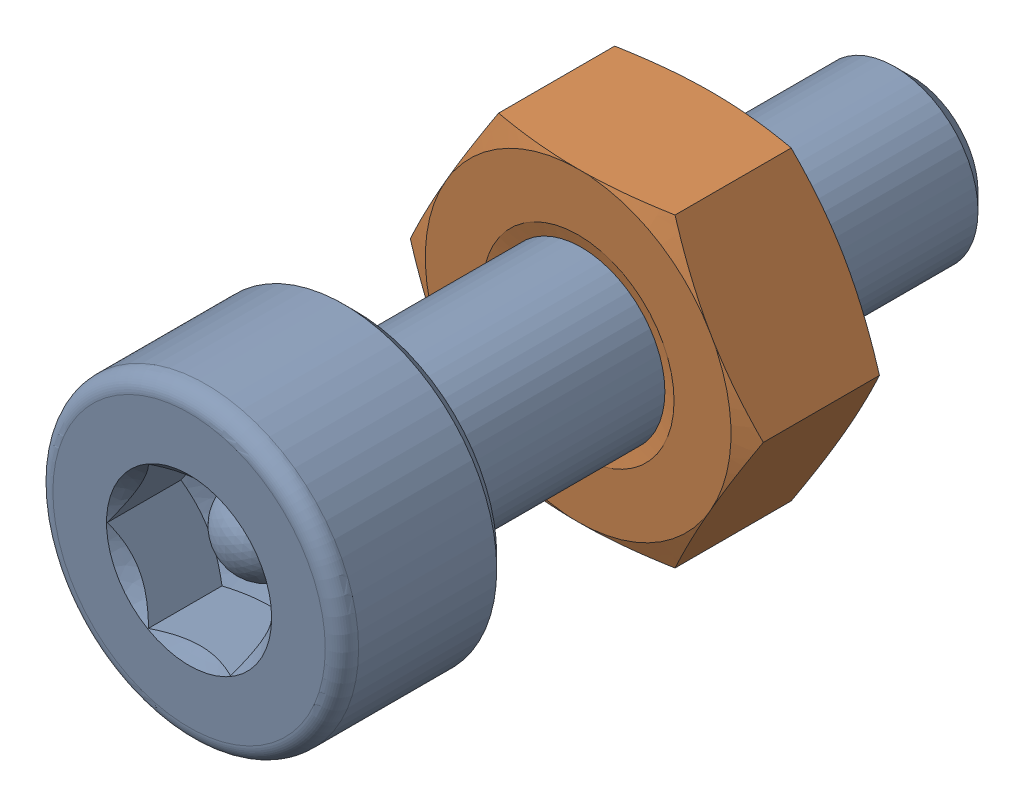
SolidWorks assembly Screw and Nut M3x010_021-1, configuration Varsayılan. Lengths in mm.
Overall size (6.35 5.5 13.14).
2 component instances, 2 part files, 0 mates.
Components (placement in the parent):
- M3x10-Screw020-1-1: M3x10-Screw020-1 [Varsayılan] at origin size (5.5 5.5 13.14)
- M3-Nut052-1-1: M3-Nut052-1 [Varsayılan] at (0 0 -4) x (-1 0 0) z (0 0 -1) size (6.35 5.5 2.4)
